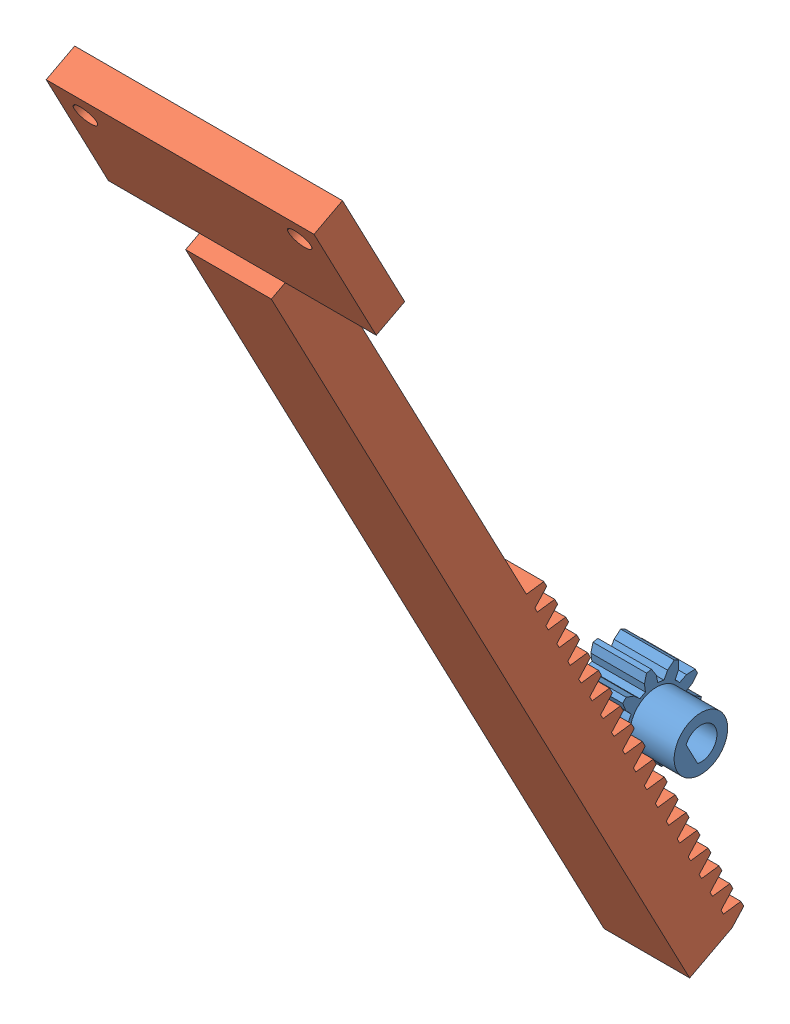
SolidWorks assembly pignon crémaillère, configuration Défaut. Lengths in mm.
Overall size (25 88.26 50.37).
2 component instances, 2 part files, 3 mates.
Components (placement in the parent):
- roue dentée-1: roue dentée [Défaut] at (-20.2248 29.8372 154.8626) x (1 0.000006 0.000009) z (0.000005 0.464705 -0.885466) size (9.14 8.12 8.4)
- crémaillère-3: crémaillère [Défaut] at (-20.7242 -39.2906 128.7602) x (-0.000009 0.885466 0.464705) z (-1 -0.000006 -0.000009) size (96.53 6 25)
Mates (geometry in assembly coordinates):
- Coïncidente1: coincident aligned: plane of roue dentée-1 through (-22.7248 29.8372 154.8626) normal (-1 -0.000006 -0.000009); plane of crémaillère-3 through (-22.7255 86.7471 189.8697) normal (-1 -0.000006 -0.000009)
- Parallèle1: parallel anti-aligned: line of roue dentée-1 through (-22.7248 30.4236 156.2432) axis (0.000009 -0.885466 -0.464705); line of crémaillère-3 through (-22.7247 10.2706 154.7706) axis (-0.000009 0.885466 0.464705)
- Contrainte pignon-crémaillère1: rack pinion = 3 mm: line of crémaillère-3 through (-22.7247 10.2706 154.7706) axis (-0.000009 0.885466 0.464705); circle of roue dentée-1
